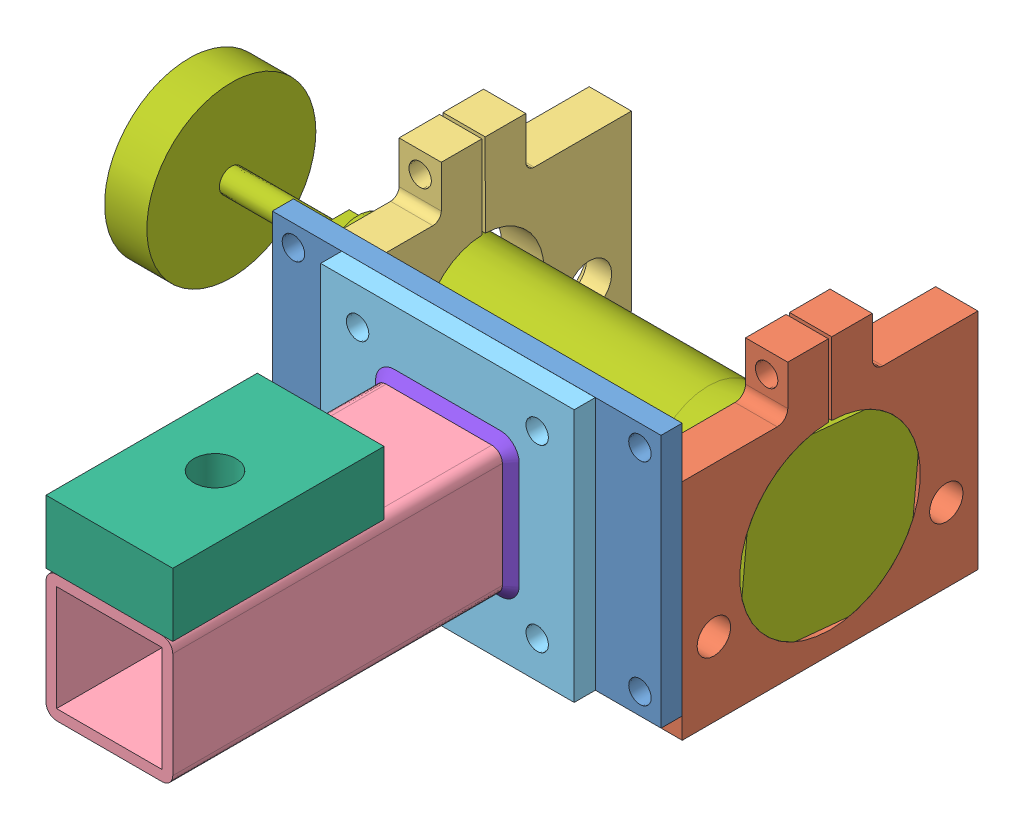
SolidWorks assembly Toolpost_Grinder_Asm, configuration Default. Lengths in mm.
Overall size (192.68 82.56 203.2).
8 component instances, 8 part files, 14 mates.
Components (placement in the parent):
- Grinder_Side_Plate-1: Grinder_Side_Plate [Default] at (-38.1179 -64.8163 -199.7024) x (-1 -0.000307 0) z (0 0 -1) size (116.84 76.2 6.35)
- Large_Hole_Plate-1: Large_Hole_Plate [Default] at (20.303 -67.9734 -250.5024) x (-0.000307 1 0) z (-1 -0.000307 0) size (82.55 88.9 19.05)
- Small_Hole_Plate-1: Small_Hole_Plate [Default] at (-83.8393 -60.3854 -250.5024) x (-0.000307 1 0) z (-1 -0.000307 0) size (67.31 88.9 19.05)
- Square_Tube-1: Square_Tube [Default] at (-37.5617 -64.8316 -193.3524) size (38.1 38.1 101.6)
- Square_Tube_End_Plate-1: Square_Tube_End_Plate [Default] at (-37.5617 -64.8316 -193.3524) x (-1 0 0) z (0 0 -1) size (76.2 76.2 6.35)
- Square_Tube_Spacer_Block-1: Square_Tube_Spacer_Block [Default] at (-37.5617 -45.7816 -123.5024) x (1 0 0) z (0 1 0) size (38.1 63.5 19.05)
- Grinder-1: Grinder [Default] at (-96.1536 -75.6292 -250.5024) x (0.00003 -0.096562 -0.995327) z (-0.000306 0.995327 -0.096562) size (51.69 192.66 51.69)
- bead2-1: bead2 [Default] at origin size (43.84 43.84 2.72)
Mates (geometry in assembly coordinates):
- Coincident1: coincident anti-aligned: plane of Grinder_Side_Plate-1 through (-96.5497 -26.7343 -206.0524) normal (0 0 -1); plane of Small_Hole_Plate-1 through (-96.529 -94.0443 -206.0524) normal (0 0 1)
- Coincident2: coincident anti-aligned: plane of Grinder_Side_Plate-1 through (-96.5497 -26.7343 -206.0524) normal (0 0 -1); plane of Large_Hole_Plate-1 through (7.6157 -109.2523 -206.0524) normal (0 0 1)
- Coincident3: coincident aligned: axis of Grinder_Side_Plate-1 through (-90.1977 -33.0823 -199.7024) axis (0 0 -1); axis of Small_Hole_Plate-1 through (-90.1977 -33.0823 -237.8024) axis (0 0 -1)
- Coincident4: coincident: axis of Grinder_Side_Plate-1 through (-90.1782 -96.5823 -199.7024) axis (0 0 -1); axis of Small_Hole_Plate-1 through (-90.1782 -96.5823 -223.8324) axis (0 0 1)
- Coincident5: coincident aligned: axis of Grinder_Side_Plate-1 through (13.9423 -33.0503 -199.7024) axis (0 0 -1); axis of Large_Hole_Plate-1 through (13.9423 -33.0503 -237.8024) axis (0 0 -1)
- Coincident6: coincident: axis of Grinder_Side_Plate-1 through (13.9618 -96.5503 -199.7024) axis (0 0 -1); axis of Large_Hole_Plate-1 through (13.9618 -96.5503 -223.8324) axis (0 0 1)
- Coincident11: coincident: point of Square_Tube-1; point of Square_Tube_End_Plate-1
- Coincident12: coincident anti-aligned: plane of Square_Tube-1 through (-18.5117 -45.7816 -193.3524) normal (0 0 -1); plane of Square_Tube_End_Plate-1 through (-75.6617 -26.7316 -193.3524) normal (0 0 1)
- Parallel1: parallel aligned: plane of Square_Tube-1 through (-18.5117 -83.8816 -91.7524) normal (1 0 0); plane of Square_Tube_End_Plate-1 through (0.5383 -102.9316 -199.7024) normal (1 0 0)
- Coincident14: coincident anti-aligned: plane of Grinder_Side_Plate-1 through (-96.5497 -26.7343 -199.7024) normal (0 0 1); plane of Square_Tube_End_Plate-1 through (-75.6617 -26.7316 -199.7024) normal (0 0 -1)
- Coincident15: coincident anti-aligned: plane of Square_Tube-1 through (-56.6117 -45.7816 -91.7524) normal (0 1 0); plane of Square_Tube_Spacer_Block-1 through (-18.5117 -45.7816 -155.2524) normal (0 -1 0)
- Coincident16: coincident aligned: axis of Square_Tube-1 through (-37.5617 -45.7816 -123.5024) axis (0 -1 0); axis of Square_Tube_Spacer_Block-1 through (-37.5617 -26.7316 -123.5024) axis (0 -1 0)
- Coincident17: coincident anti-aligned: axis of Large_Hole_Plate-1 through (20.3054 -75.5934 -250.5024) axis (-1 -0.000307 0); axis of Grinder-1 through (7.3514 -75.5974 -250.5024) axis (1 0.000307 0)
- Coincident18: coincident aligned: plane of Large_Hole_Plate-1 through (20.2903 -26.6984 -294.9524) normal (1 0.000307 0); plane of Grinder-1 through (20.3046 -72.9751 -223.5146) normal (1 0.000307 0)
